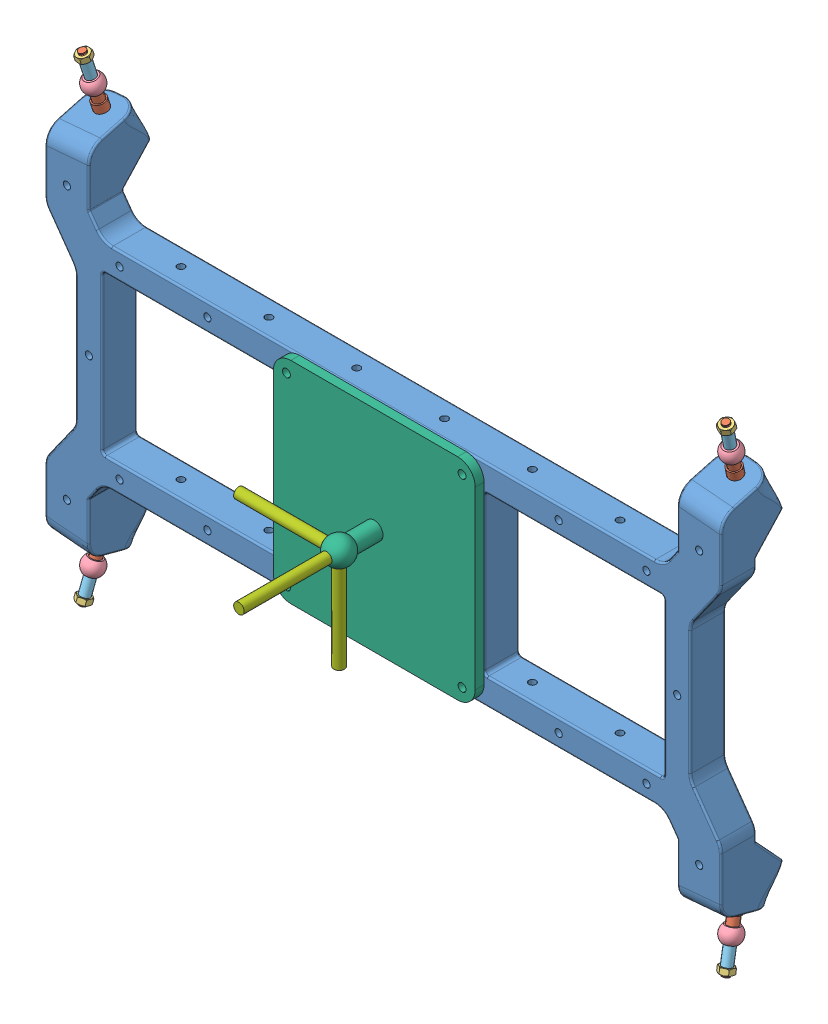
SolidWorks assembly platform, configuration Default. Lengths in mm.
Overall size (386.02 276.21 117.43).
25 component instances, 7 part files, 56 mates.
Components (placement in the parent):
- demo_platform_2022-10-06-1: demo_platform_2022-10-06 [Standard] at origin size (386.02 217.26 35.36)
- pin_ball_bearing_2022-06-03-1: pin_ball_bearing_2022-06-03 [Default] at (180.4737 105.4145 -10.2844) x (0.084186 0.96225 0.258819) z (-0.258819 -0.22971 0.938214) size (57.5 7.5 7.5)
- pin_ball_bearing_2022-06-03-2: pin_ball_bearing_2022-06-03 [Default] at (-180.4737 105.4145 -10.2844) x (-0.084186 0.96225 0.258819) z (-0.655126 -0.249161 0.713252) size (57.5 7.5 7.5)
- pin_ball_bearing_2022-06-03-3: pin_ball_bearing_2022-06-03 [Default] at (-180.4737 -105.4145 -10.2844) x (-0.084186 -0.96225 0.258819) z (-0.795763 0.221252 0.563746) size (57.5 7.5 7.5)
- pin_ball_bearing_2022-06-03-4: pin_ball_bearing_2022-06-03 [Default] at (180.4737 -105.4145 -10.2844) x (0.084186 -0.96225 0.258819) z (-0.258819 0.22971 0.938214) size (57.5 7.5 7.5)
- hex nut style 1 gradeab_din-1: hex nut style 1 gradeab_din [Hexagon Nut ISO 4032 - M5 - D - N] at (-178.8152 -86.4582 -15.3832) x (0.862951 0.059466 0.501776) z (0.084186 0.96225 -0.258819) size (8 9.24 4.7)
- hex nut style 1 gradeab_din-2: hex nut style 1 gradeab_din [Hexagon Nut ISO 4032 - M5 - D - N] at (179.2109 -90.9808 -14.1667) x (0.862951 0.200275 0.463902) z (0.084186 -0.96225 0.258819) size (8 9.24 4.7)
- hex nut style 1 gradeab_din-3: hex nut style 1 gradeab_din [Hexagon Nut ISO 4032 - M5 - D - N] at (178.8152 86.4582 -15.3832) x (0.862951 -0.200275 0.463902) z (-0.084186 -0.96225 -0.258819) size (8 9.24 4.7)
- hex nut style 1 gradeab_din-4: hex nut style 1 gradeab_din [Hexagon Nut ISO 4032 - M5 - D - N] at (-178.8152 86.4582 -15.3832) x (0.862951 -0.059466 0.501776) z (0.084186 -0.96225 -0.258819) size (8 9.24 4.7)
- IGUS_KGLM-05_inner_shell-1: IGUS_KGLM-05_inner_shell [Default] at (181.6523 118.886 -6.661) x (0.084186 0.96225 0.258819) z (-0.616127 -0.15387 0.772471) size (8 11 11)
- IGUS_KGLM-05_inner_shell-2: IGUS_KGLM-05_inner_shell [Default] at (181.6523 -118.886 -6.661) x (-0.084186 0.96225 -0.258819) z (-0.650943 0.14355 0.74543) size (8 11 11)
- IGUS_KGLM-05_inner_shell-3: IGUS_KGLM-05_inner_shell [Default] at (-181.6523 -118.886 -6.661) x (0.084186 0.96225 -0.258819) z (-0.616127 0.254404 0.74543) size (8 11 11)
- IGUS_KGLM-05_inner_shell-4: IGUS_KGLM-05_inner_shell [Default] at (-181.6523 118.886 -6.661) x (0.084186 -0.96225 -0.258819) z (-0.209588 0.236831 -0.948675) size (8 11 11)
- tube_ball_bearing_2022-06-07-1: tube_ball_bearing_2022-06-07 [Default] at (181.9891 122.735 -5.6257) x (0.996388 -0.078397 -0.032626) z (0.011104 -0.260631 0.965375) size (5.5 10 5.5)
- tube_ball_bearing_2022-06-07-2: tube_ball_bearing_2022-06-07 [Default] at (-182.8309 132.3575 -3.0375) x (-0.890277 0.044033 -0.453287) z (-0.447572 -0.268581 0.852962) size (5.5 10 5.5)
- tube_ball_bearing_2022-06-07-3: tube_ball_bearing_2022-06-07 [Default] at (181.9891 -122.735 -5.6257) x (-0.813172 -0.216462 -0.540273) z (-0.575902 0.164981 0.800698) size (5.5 10 5.5)
- tube_ball_bearing_2022-06-07-4: tube_ball_bearing_2022-06-07 [Default] at (-181.9891 -122.735 -5.6257) x (-0.778961 -0.098425 -0.6193) z (-0.621396 0.253746 0.741269) size (5.5 10 5.5)
- hex nut style 1 gradeab_din-5: hex nut style 1 gradeab_din [Hexagon Nut ISO 4032 - M4 - D - N] at (-183.1003 135.4367 -2.2093) x (-0.823764 0.078934 -0.56141) z (-0.084186 0.96225 0.258819) size (7 8.08 3.2)
- hex nut style 1 gradeab_din-6: hex nut style 1 gradeab_din [Hexagon Nut ISO 4032 - M4 - D - N] at (182.8309 132.3575 -3.0375) x (0.982463 -0.036789 -0.182791) z (-0.084186 -0.96225 -0.258819) size (7 8.08 3.2)
- hex nut style 1 gradeab_din-7: hex nut style 1 gradeab_din [Hexagon Nut ISO 4032 - M4 - D - N] at (183.1003 -135.4367 -2.2093) x (-0.995063 -0.094885 -0.029103) z (0.084186 -0.96225 0.258819) size (7 8.08 3.2)
- hex nut style 1 gradeab_din-8: hex nut style 1 gradeab_din [Hexagon Nut ISO 4032 - M4 - D - N] at (-183.1003 -135.4367 -2.2093) x (-0.99437 0.064352 -0.084186) z (-0.084186 -0.96225 0.258819) size (7 8.08 3.2)
- demo_platform_coordinate_system-2: demo_platform_coordinate_system [Default] at (0 -0.0011 15) x (-1 0 0) z (0 0 1) size (115 120 32.07)
- demo_platform_axis-1: demo_platform_axis [Default] at (0 -3.0722 35) x (-0.837169 0 -0.546944) z (-0.546944 0 0.837169) size (6 54 6)
- demo_platform_axis-2: demo_platform_axis [Default] at (0 -0.0011 38.0711) x (-0.923728 -0.383049 0) z (-0.383049 0.923728 0) size (6 54 6)
- demo_platform_axis-3: demo_platform_axis [Default] at (-3.0711 -0.0011 35) x (0 -0.381849 0.924225) z (0 -0.924225 -0.381849) size (6 54 6)
Mates (geometry in assembly coordinates):
- Concentric1: concentric anti-aligned: cylinder of demo_platform_2022-10-06-1 through (185.6401 164.4666 5.599) axis (0.084186 0.96225 0.258819) radius 2.6; cylinder of pin_ball_bearing_2022-06-03-1 through (178.3888 81.584 -16.6942) axis (-0.084186 -0.96225 -0.258819) radius 2.5
- Coincident1: coincident anti-aligned: plane of demo_platform_2022-10-06-1 through (238.2924 94.9001 10) normal (0.084186 0.96225 0.258819); plane of pin_ball_bearing_2022-06-03-1 through (178.0681 105.7794 -10.8587) normal (-0.084186 -0.96225 -0.258819)
- Concentric2: concentric anti-aligned: cylinder of demo_platform_2022-10-06-1 through (-185.6401 164.4666 5.599) axis (-0.084186 0.96225 0.258819) radius 2.6; cylinder of pin_ball_bearing_2022-06-03-2 through (-178.3888 81.584 -16.6942) axis (0.084186 -0.96225 -0.258819) radius 2.5
- Coincident2: coincident anti-aligned: plane of demo_platform_2022-10-06-1 through (-238.2924 94.9001 10) normal (-0.084186 0.96225 0.258819); plane of pin_ball_bearing_2022-06-03-2 through (-182.3507 105.6883 -11.9129) normal (0.084186 -0.96225 -0.258819)
- Concentric3: concentric anti-aligned: cylinder of demo_platform_2022-10-06-1 through (185.6401 -164.4666 5.599) axis (0.084186 -0.96225 0.258819) radius 2.6; cylinder of pin_ball_bearing_2022-06-03-4 through (178.3888 -81.584 -16.6942) axis (-0.084186 0.96225 -0.258819) radius 2.5
- Coincident3: coincident anti-aligned: plane of demo_platform_2022-10-06-1 through (238.2924 -94.9001 10) normal (0.084186 -0.96225 0.258819); plane of pin_ball_bearing_2022-06-03-4 through (182.8793 -105.0496 -9.7102) normal (-0.084186 0.96225 -0.258819)
- Concentric4: concentric anti-aligned: cylinder of demo_platform_2022-10-06-1 through (-185.6401 -164.4666 5.599) axis (-0.084186 -0.96225 0.258819) radius 2.6; cylinder of pin_ball_bearing_2022-06-03-3 through (-178.3888 -81.584 -16.6942) axis (0.084186 0.96225 -0.258819) radius 2.5
- Coincident4: coincident anti-aligned: plane of demo_platform_2022-10-06-1 through (-238.2924 -94.9001 10) normal (-0.084186 -0.96225 0.258819); plane of pin_ball_bearing_2022-06-03-3 through (-178.9744 -105.0183 -8.3236) normal (0.084186 0.96225 -0.258819)
- Concentric5: concentric aligned: cylinder of pin_ball_bearing_2022-06-03-3 through (-178.3888 -81.584 -16.6942) axis (0.084186 0.96225 -0.258819) radius 2.5; cylinder of hex nut style 1 gradeab_din-1 through (-179.2109 -90.9808 -14.1667) axis (0.084186 0.96225 -0.258819) radius 2.1
- Coincident5: coincident anti-aligned: plane of demo_platform_2022-10-06-1 through (-8.3316 -95.2307 25.6145) normal (0.084186 0.96225 -0.258819); plane of hex nut style 1 gradeab_din-1 through (-176.9097 -92.2075 -17.9789) normal (-0.084186 -0.96225 0.258819)
- Parallel1: parallel anti-aligned: plane of demo_platform_2022-10-06-1 through (-181.6847 -91.8958 -18.3734) normal (0 0.259741 0.965678); plane of hex nut style 1 gradeab_din-1 through (-176.9097 -92.2075 -17.9789) normal (0 -0.259741 -0.965678)
- Concentric7: concentric anti-aligned: cylinder of pin_ball_bearing_2022-06-03-4 through (178.3888 -81.584 -16.6942) axis (-0.084186 0.96225 -0.258819) radius 2.5; cylinder of hex nut style 1 gradeab_din-2 through (178.8152 -86.4582 -15.3832) axis (0.084186 -0.96225 0.258819) radius 2.1
- Coincident7: coincident anti-aligned: plane of demo_platform_2022-10-06-1 through (8.3316 -95.2307 25.6145) normal (-0.084186 0.96225 -0.258819); plane of hex nut style 1 gradeab_din-2 through (176.9097 -90.1295 -10.2535) normal (0.084186 -0.96225 0.258819)
- Parallel2: parallel anti-aligned: plane of demo_platform_2022-10-06-1 through (181.6847 -91.8958 -18.3734) normal (0 0.259741 0.965678); plane of hex nut style 1 gradeab_din-2 through (176.514 -87.6849 -19.1954) normal (0 -0.259741 -0.965678)
- Concentric8: concentric aligned: cylinder of pin_ball_bearing_2022-06-03-1 through (178.3888 81.584 -16.6942) axis (-0.084186 -0.96225 -0.258819) radius 2; cylinder of hex nut style 1 gradeab_din-3 through (179.2109 90.9808 -14.1667) axis (-0.084186 -0.96225 -0.258819) radius 2.1
- Coincident9: coincident anti-aligned: plane of demo_platform_2022-10-06-1 through (8.3316 95.2307 25.6145) normal (-0.084186 -0.96225 -0.258819); plane of hex nut style 1 gradeab_din-3 through (176.9097 90.1295 -10.2535) normal (0.084186 0.96225 0.258819)
- Parallel3: parallel anti-aligned: plane of demo_platform_2022-10-06-1 through (181.6847 91.8958 -18.3734) normal (0 -0.259741 0.965678); plane of hex nut style 1 gradeab_din-3 through (176.9097 92.2075 -17.9789) normal (0 0.259741 -0.965678)
- Concentric9: concentric aligned: cylinder of pin_ball_bearing_2022-06-03-2 through (-178.3888 81.584 -16.6942) axis (0.084186 -0.96225 -0.258819) radius 2; cylinder of hex nut style 1 gradeab_din-4 through (-179.2109 90.9808 -14.1667) axis (0.084186 -0.96225 -0.258819) radius 2.1
- Coincident11: coincident anti-aligned: plane of demo_platform_2022-10-06-1 through (-8.3316 95.2307 25.6145) normal (0.084186 -0.96225 -0.258819); plane of hex nut style 1 gradeab_din-4 through (-181.5121 89.7541 -10.3545) normal (-0.084186 0.96225 0.258819)
- Parallel4: parallel anti-aligned: plane of demo_platform_2022-10-06-1 through (-181.6847 91.8958 -18.3734) normal (0 -0.259741 0.965678); plane of hex nut style 1 gradeab_din-4 through (-181.5121 91.832 -18.0799) normal (0 0.259741 -0.965678)
- Concentric10: concentric aligned: cylinder of pin_ball_bearing_2022-06-03-1 through (178.3888 81.584 -16.6942) axis (-0.084186 -0.96225 -0.258819) radius 2.5; cylinder of IGUS_KGLM-05_inner_shell-1 through (181.1407 113.0383 -8.2339) axis (-0.084186 -0.96225 -0.258819) radius 2.5
- Coincident13: coincident anti-aligned: plane of pin_ball_bearing_2022-06-03-1 through (178.4288 115.4749 -8.3854) normal (0.084186 0.96225 0.258819); plane of IGUS_KGLM-05_inner_shell-1 through (178.3593 115.8845 -9.8854) normal (-0.084186 -0.96225 -0.258819)
- Concentric11: concentric anti-aligned: cylinder of pin_ball_bearing_2022-06-03-4 through (178.3888 -81.584 -16.6942) axis (-0.084186 0.96225 -0.258819) radius 2.5; cylinder of IGUS_KGLM-05_inner_shell-2 through (182.1639 -124.7337 -5.0881) axis (0.084186 -0.96225 0.258819) radius 2.5
- Coincident14: coincident anti-aligned: plane of pin_ball_bearing_2022-06-03-4 through (184.2023 -114.5991 -7.0071) normal (0.084186 -0.96225 0.258819); plane of IGUS_KGLM-05_inner_shell-2 through (178.4676 -115.9099 -10.0151) normal (-0.084186 0.96225 -0.258819)
- Concentric12: concentric anti-aligned: cylinder of pin_ball_bearing_2022-06-03-3 through (-178.3888 -81.584 -16.6942) axis (0.084186 0.96225 -0.258819) radius 2.5; cylinder of IGUS_KGLM-05_inner_shell-3 through (-182.1639 -124.7337 -5.0881) axis (-0.084186 -0.96225 0.258819) radius 2.5
- Coincident16: coincident anti-aligned: plane of pin_ball_bearing_2022-06-03-3 through (-179.5164 -114.5615 -5.3432) normal (-0.084186 -0.96225 0.258819); plane of IGUS_KGLM-05_inner_shell-3 through (-184.2718 -115.4021 -10.0151) normal (0.084186 0.96225 -0.258819)
- Concentric13: concentric anti-aligned: cylinder of pin_ball_bearing_2022-06-03-2 through (-178.3888 81.584 -16.6942) axis (0.084186 -0.96225 -0.258819) radius 2.5; cylinder of IGUS_KGLM-05_inner_shell-4 through (-182.1639 124.7337 -5.0881) axis (-0.084186 0.96225 0.258819) radius 2.5
- Coincident17: coincident anti-aligned: plane of pin_ball_bearing_2022-06-03-2 through (-183.568 115.3656 -9.6504) normal (-0.084186 0.96225 0.258819); plane of IGUS_KGLM-05_inner_shell-4 through (-184.9929 114.5308 -7.0102) normal (0.084186 -0.96225 -0.258819)
- Coincident18: coincident anti-aligned: plane of IGUS_KGLM-05_inner_shell-3 through (-184.9453 -123.1001 -7.9446) normal (-0.084186 -0.96225 0.258819); plane of tube_ball_bearing_2022-06-07-4 through (-181.9891 -122.735 -5.6257) normal (0.084186 0.96225 -0.258819)
- Concentric15: concentric aligned: cylinder of pin_ball_bearing_2022-06-03-3 through (-178.3888 -81.584 -16.6942) axis (0.084186 0.96225 -0.258819) radius 3; cylinder of tube_ball_bearing_2022-06-07-4 through (-182.8309 -132.3575 -3.0375) axis (0.084186 0.96225 -0.258819) radius 2.75
- Coincident19: coincident anti-aligned: plane of IGUS_KGLM-05_inner_shell-2 through (179.1411 -123.6079 -7.9446) normal (0.084186 -0.96225 0.258819); plane of tube_ball_bearing_2022-06-07-3 through (181.9891 -122.735 -5.6257) normal (-0.084186 0.96225 -0.258819)
- Concentric16: concentric aligned: cylinder of pin_ball_bearing_2022-06-03-4 through (178.3888 -81.584 -16.6942) axis (-0.084186 0.96225 -0.258819) radius 3; cylinder of tube_ball_bearing_2022-06-07-3 through (182.8309 -132.3575 -3.0375) axis (-0.084186 0.96225 -0.258819) radius 2.75
- Coincident20: coincident anti-aligned: plane of IGUS_KGLM-05_inner_shell-1 through (179.0328 123.5825 -7.8148) normal (0.084186 0.96225 0.258819); plane of tube_ball_bearing_2022-06-07-1 through (181.9891 122.735 -5.6257) normal (-0.084186 -0.96225 -0.258819)
- Concentric17: concentric aligned: cylinder of pin_ball_bearing_2022-06-03-1 through (178.3888 81.584 -16.6942) axis (-0.084186 -0.96225 -0.258819) radius 3; cylinder of tube_ball_bearing_2022-06-07-1 through (182.8309 132.3575 -3.0375) axis (-0.084186 -0.96225 -0.258819) radius 2.75
- Coincident22: coincident anti-aligned: plane of IGUS_KGLM-05_inner_shell-4 through (-185.6664 122.2288 -4.9397) normal (-0.084186 0.96225 0.258819); plane of tube_ball_bearing_2022-06-07-2 through (-181.9891 122.735 -5.6257) normal (0.084186 -0.96225 -0.258819)
- Concentric18: concentric anti-aligned: cylinder of pin_ball_bearing_2022-06-03-2 through (-178.3888 81.584 -16.6942) axis (0.084186 -0.96225 -0.258819) radius 3; cylinder of tube_ball_bearing_2022-06-07-2 through (-181.9891 122.735 -5.6257) axis (-0.084186 0.96225 0.258819) radius 2.75
- Concentric19: concentric anti-aligned: cylinder of pin_ball_bearing_2022-06-03-3 through (-178.3888 -81.584 -16.6942) axis (0.084186 0.96225 -0.258819) radius 3; cylinder of hex nut style 1 gradeab_din-8 through (-182.8309 -132.3575 -3.0375) axis (-0.084186 -0.96225 0.258819) radius 1.65
- Coincident23: coincident anti-aligned: plane of tube_ball_bearing_2022-06-07-4 through (-182.8309 -132.3575 -3.0375) normal (-0.084186 -0.96225 0.258819); plane of hex nut style 1 gradeab_din-8 through (-182.5708 -133.4263 -6.9264) normal (0.084186 0.96225 -0.258819)
- Concentric20: concentric anti-aligned: cylinder of pin_ball_bearing_2022-06-03-4 through (178.3888 -81.584 -16.6942) axis (-0.084186 0.96225 -0.258819) radius 3; cylinder of hex nut style 1 gradeab_din-7 through (182.8309 -132.3575 -3.0375) axis (0.084186 -0.96225 0.258819) radius 1.65
- Coincident24: coincident anti-aligned: plane of tube_ball_bearing_2022-06-07-3 through (182.8309 -132.3575 -3.0375) normal (0.084186 -0.96225 0.258819); plane of hex nut style 1 gradeab_din-7 through (183.0433 -133.3885 -6.9395) normal (-0.084186 0.96225 -0.258819)
- Coincident25: coincident anti-aligned: plane of tube_ball_bearing_2022-06-07-2 through (-182.8309 132.3575 -3.0375) normal (-0.084186 0.96225 0.258819); plane of hex nut style 1 gradeab_din-5 through (-185.0967 131.3049 0.1392) normal (0.084186 -0.96225 -0.258819)
- Concentric22: concentric anti-aligned: cylinder of pin_ball_bearing_2022-06-03-2 through (-178.3888 81.584 -16.6942) axis (0.084186 -0.96225 -0.258819) radius 3; cylinder of hex nut style 1 gradeab_din-5 through (-182.8309 132.3575 -3.0375) axis (-0.084186 0.96225 0.258819) radius 1.65
- Coincident26: coincident anti-aligned: plane of tube_ball_bearing_2022-06-07-1 through (182.8309 132.3575 -3.0375) normal (0.084186 0.96225 0.258819); plane of hex nut style 1 gradeab_din-6 through (183.5033 131.2677 0.7957) normal (-0.084186 -0.96225 -0.258819)
- Concentric23: concentric aligned: cylinder of pin_ball_bearing_2022-06-03-1 through (178.3888 81.584 -16.6942) axis (-0.084186 -0.96225 -0.258819) radius 3; cylinder of hex nut style 1 gradeab_din-6 through (183.1003 135.4367 -2.2093) axis (-0.084186 -0.96225 -0.258819) radius 1.65
- Concentric28: concentric anti-aligned: cylinder of demo_platform_coordinate_system-2 through (-50 52.4989 10) axis (0 0 1) radius 2.25; cylinder of demo_platform_2022-10-06-1 through (-50 52.4989 10) axis (0 0 -1) radius 2.05
- Parallel8: parallel anti-aligned: plane of demo_platform_2022-10-06-1 through (-159.6617 -60 -10) normal (0 -1 0); plane of demo_platform_coordinate_system-2 through (57.5 59.9989 10) normal (0 1 0)
- Coincident30: coincident anti-aligned: plane of demo_platform_2022-10-06-1 through (0 0 10) normal (0 0 1); plane of demo_platform_coordinate_system-2 through (0 -0.0011 10) normal (0 0 -1)
- Concentric29: concentric aligned: cylinder of demo_platform_coordinate_system-2 through (0 -42.1787 35) axis (0 -1 0) radius 2.5; cylinder of demo_platform_axis-1 through (0 -51.9676 35) axis (0 -1 0) radius 3
- Coincident31: coincident aligned: circle of demo_platform_coordinate_system-2; circle of demo_platform_axis-1
- Concentric30: concentric aligned: cylinder of demo_platform_coordinate_system-2 through (0 -0.0011 61.426) axis (0 0 1) radius 2.5; cylinder of demo_platform_axis-2 through (0 -0.0011 86.9665) axis (0 0 1) radius 3
- Coincident32: coincident aligned: circle of demo_platform_coordinate_system-2; circle of demo_platform_axis-2
- Concentric31: concentric anti-aligned: cylinder of demo_platform_coordinate_system-2 through (16.0302 -0.0011 35) axis (1 0 0) radius 2.5; cylinder of demo_platform_axis-3 through (-51.9665 -0.0011 35) axis (-1 0 0) radius 3
- Coincident33: coincident aligned: circle of demo_platform_coordinate_system-2; circle of demo_platform_axis-3
- Coincident34: coincident aligned: plane of demo_platform_2022-10-06-1 through (0 0 0) normal (0 0 1)
- Coincident35: coincident aligned: plane of demo_platform_2022-10-06-1 through (0 0 0) normal (0 1 0)
- Coincident36: coincident aligned: plane of demo_platform_2022-10-06-1 through (0 0 0) normal (1 0 0)
